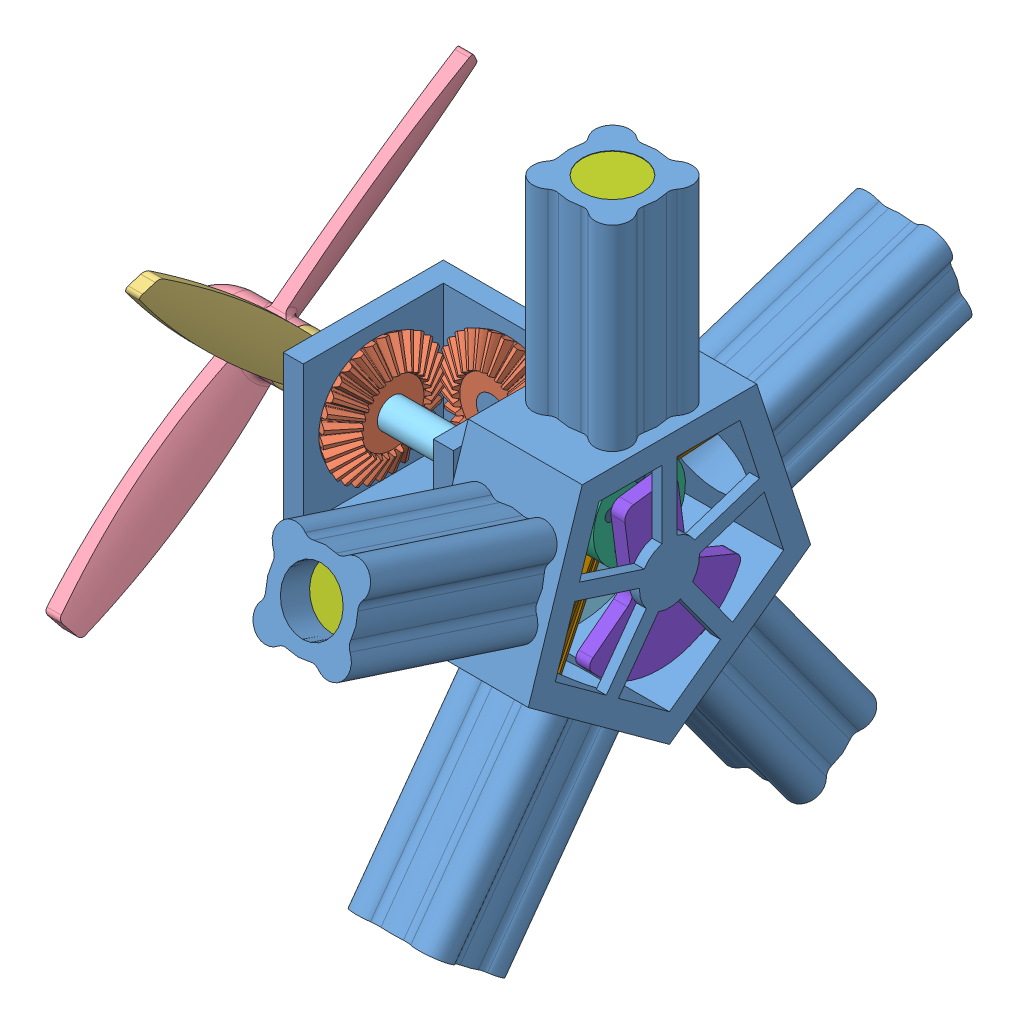
SolidWorks assembly Assembly, configuration Default. Lengths in mm.
Overall size (240.66 300.05 315.49).
28 component instances, 11 part files, 64 mates.
Components (placement in the parent):
- Frame-5: Frame [Default] at (-31.9834 -30.097 217.4511) size (157 300.05 315.49)
- straight bevel gear_am-6: straight bevel gear_am [Bear Propeller Gear] at (10.5166 12.403 147.4521) x (-0.00003 0 1) z (0.262129 0.965033 0.000008) size (11.62 61.25 61.4)
- straight bevel gear_am-7: straight bevel gear_am [Bear Propeller Gear] at (43.0165 12.4031 181.451) x (-1 0 0) z (0 -0.266038 -0.963962) size (11.62 61.25 61.4)
- straight bevel gear_am-8: straight bevel gear_am [Bear Propeller Gear] at (-21.983 12.4031 181.4509) x (1 0 0) z (0 0.96742 -0.253176) size (11.62 61.25 61.4)
- Rear Propeller-1: Rear Propeller [Default] at (-31.9833 12.403 181.4511) x (0 0.679303 0.733858) z (-1 0 0) size (250 25.61 44.95)
- Front Propeller-1: Front Propeller [Default] at (-61.9833 12.403 181.4511) x (0 0.580851 -0.81401) z (-1 0 0) size (250 25.46 57.93)
- Crankshaft Counterweight-1: Crankshaft Counterweight [Default] at (80.0167 45.3295 199.3866) x (0 0.131567 -0.991307) z (-1 0 0) size (75.99 79.21 165)
- Rod Hub-1: Rod Hub [Default] at (80.0167 35.2031 184.4771) x (0 0.608872 0.793269) z (1 0 0) size (97.09 122.53 33)
- Piston-1: Piston [Default] at (96.5166 170.1518 181.4511) x (0 0 1) z (-1 0 0) size (30 35 30)
- Base Counterweight-2: Base Counterweight [Default] at (120.0166 45.3295 199.3866) x (0 0.131567 -0.991307) z (-1 0 0) size (75.99 79.21 47)
- Connecting Rod-2: Connecting Rod [Default] at (96.5167 40.2083 198.6052) x (0 0.100944 0.994892) z (-1 0 0) size (111 13 15)
- Piston-2: Piston [Default] at (96.5166 56.4831 317.1156) x (0 -0.951057 0.309017) z (-1 0 0) size (30 35 30)
- Connecting Rod-3: Connecting Rod [Default] at (96.5167 39.4581 170.1052) x (0 0.089918 -0.995949) z (-1 0 0) size (111 13 15)
- Piston-3: Piston [Default] at (96.5166 54.6302 51.4892) x (0 0.951057 0.309017) z (-1 0 0) size (30 35 30)
- Connecting Rod-4: Connecting Rod [Default] at (96.5167 23.3132 193.6032) x (0 -0.893752 0.448561) z (-1 0 0) size (111 13 15)
- Piston-4: Piston [Default] at (96.5166 -82.2424 250.215) x (0 -0.587785 -0.809017) z (-1 0 0) size (30 35 30)
- Connecting Rod-5: Connecting Rod [Default] at (96.5167 22.8495 175.9892) x (0 -0.866559 -0.499075) z (-1 0 0) size (111 13 15)
- Piston-5: Piston [Default] at (96.5166 -79.9867 114.326) x (0 0.587785 -0.809017) z (-1 0 0) size (30 35 30)
- Hub Pin-1: Hub Pin [Default] at (113.0167 23.3132 193.6032) x (0 0 1) z (-1 0 0) size (6 6 33)
- Hub Pin-2: Hub Pin [Default] at (113.0167 50.1864 184.0827) x (0 0 1) z (-1 0 0) size (6 6 33)
- Hub Pin-3: Hub Pin [Default] at (113.0167 39.4581 170.1052) x (0 0 1) z (-1 0 0) size (6 6 33)
- Hub Pin-4: Hub Pin [Default] at (113.0167 22.8495 175.9892) x (0 0 1) z (-1 0 0) size (6 6 33)
- Hub Pin-5: Hub Pin [Default] at (113.0167 40.2083 198.6052) x (0 0 1) z (-1 0 0) size (6 6 33)
- Piston Pin-1: Piston Pin [Default] at (110.3518 150.1518 181.4511) x (0 0.805023 0.593243) z (-1 0 0) size (10 10 28)
- Piston Pin-2: Piston Pin [Default] at (110.4932 48.4499 70.5103) x (0 0.396271 0.918134) z (-1 0 0) size (10 10 28)
- Piston Pin-3: Piston Pin [Default] at (110.3878 -63.8064 126.0817) x (0 0.161373 0.986894) z (-1 0 0) size (10 10 28)
- Piston Pin-4: Piston Pin [Default] at (110.601 -66.062 238.4593) x (0 0.559209 0.829027) z (-1 0 0) size (10 10 28)
- Piston Pin-5: Piston Pin [Default] at (110.4154 50.3028 298.0944) x (0 0.645386 0.763856) z (-1 0 0) size (10 10 28)
Mates (geometry in assembly coordinates):
- Concentric6: concentric aligned: cylinder of Frame-5 through (10.5164 12.403 155.992) axis (0.00003 0 -1) radius 7.5; cylinder of straight bevel gear_am-6 through (10.516 12.403 166.8) axis (0.00003 0 -1) radius 7.5
- Coincident3: coincident anti-aligned: plane of Frame-5 through (-21.9834 47.403 147.4511) normal (-0.00003 0 1); plane of straight bevel gear_am-6 through (10.5166 12.403 147.452) normal (0.00003 0 -1)
- Concentric7: concentric anti-aligned: cylinder of Frame-5 through (58.0166 12.403 181.4511) axis (-1 0 0) radius 7.5; cylinder of straight bevel gear_am-7 through (23.6687 12.4031 181.451) axis (1 0 0) radius 7.5
- Coincident4: coincident anti-aligned: plane of Frame-5 through (43.0166 47.403 217.4511) normal (-1 0 0); plane of straight bevel gear_am-7 through (43.0166 12.4031 181.451) normal (1 0 0)
- GearMate1: gear = 15 : 15 mm: circle of Bear Propeller Gear-6; cylinder of straight bevel gear_am-7 through (23.6687 12.4031 181.451) axis (1 0 0) radius 7.5
- Concentric8: concentric anti-aligned: cylinder of Frame-5 through (-36.9834 12.403 181.4511) axis (1 0 0) radius 9.5; cylinder of straight bevel gear_am-8 through (-2.6352 12.4031 181.4509) axis (-1 0 0) radius 7.5
- Coincident5: coincident anti-aligned: plane of Frame-5 through (-21.9834 47.403 217.4511) normal (1 0 0); plane of straight bevel gear_am-8 through (-21.9831 12.4031 181.4509) normal (-1 0 0)
- GearMate2: gear = 15 : 15 mm: cylinder of straight bevel gear_am-8 through (-2.6352 12.4031 181.4509) axis (-1 0 0) radius 7.5; cylinder of straight bevel gear_am-6 through (10.516 12.403 166.8) axis (0.00003 0 -1) radius 7.5
- Coincident6: coincident anti-aligned: plane of straight bevel gear_am-8 through (-21.9831 12.4031 181.4509) normal (-1 0 0); plane of Rear Propeller-1 through (-21.9833 12.403 181.4511) normal (1 0 0)
- Concentric9: concentric aligned: cylinder of Frame-5 through (-36.9834 12.403 181.4511) axis (1 0 0) radius 9.5; cylinder of Rear Propeller-1 through (-61.9833 12.403 181.4511) axis (1 0 0) radius 7.5
- Coincident7: coincident anti-aligned: plane of Rear Propeller-1 through (-61.9833 12.403 181.4511) normal (-1 0 0); plane of Front Propeller-1 through (-61.9833 12.403 181.4511) normal (1 0 0)
- Concentric12: concentric anti-aligned: cylinder of Crankshaft Counterweight-1 through (73.0167 35.2031 184.4771) axis (1 0 0) radius 7.5; cylinder of Rod Hub-1 through (113.0167 35.2031 184.4771) axis (-1 0 0) radius 7.5
- Coincident9: coincident anti-aligned: plane of Crankshaft Counterweight-1 through (80.0167 14.143 161.0551) normal (1 0 0); plane of Rod Hub-1 through (80.0167 35.2031 184.4771) normal (-1 0 0)
- Concentric14: concentric aligned: cylinder of Crankshaft Counterweight-1 through (73.0167 35.2031 184.4771) axis (1 0 0) radius 7.5; cylinder of Base Counterweight-2 through (73.0166 35.2031 184.4771) axis (1 0 0) radius 7.5
- Coincident11: coincident aligned: plane of Crankshaft Counterweight-1 through (73.0167 14.143 161.0551) normal (-1 0 0); plane of Base Counterweight-2 through (73.0166 35.2031 184.4771) normal (-1 0 0)
- Concentric20: concentric aligned: cylinder of Frame-5 through (113.0166 12.403 181.4511) axis (1 0 0) radius 7.5; cylinder of Base Counterweight-2 through (113.0166 12.403 181.4511) axis (1 0 0) radius 7.5
- Coincident17: coincident aligned: plane of Frame-5 through (113.0166 12.403 181.4511) normal (-1 0 0); plane of Base Counterweight-2 through (113.0166 14.143 161.0551) normal (-1 0 0)
- Lock10: lock: unknown of straight bevel gear_am-8; unknown of Rear Propeller-1
- Concentric23: concentric anti-aligned: cylinder of Frame-5 through (68.0166 12.403 181.4511) axis (-1 0 0) radius 7.5; cylinder of Crankshaft Counterweight-1 through (-84.9833 12.403 181.4511) axis (1 0 0) radius 7.5
- Lock11: lock: unknown of Front Propeller-1; unknown of Crankshaft Counterweight-1
- Lock12: lock: unknown of straight bevel gear_am-7; unknown of Crankshaft Counterweight-1
- Concentric24: concentric anti-aligned: cylinder of Frame-5 through (96.5166 170.403 181.4511) axis (0 -1 0) radius 15; cylinder of Piston-1 through (96.5166 135.1518 181.4511) axis (0 1 0) radius 15
- Concentric25: concentric anti-aligned: cylinder of Connecting Rod-2 through (89.0167 50.3028 298.0944) axis (1 0 0) radius 5; cylinder of Piston-2 through (111.5166 50.3028 298.0944) axis (-1 0 0) radius 5
- Coincident18: coincident anti-aligned: plane of Connecting Rod-2 through (89.0167 40.2083 198.6052) normal (-1 0 0); plane of Piston-2 through (89.0166 54.1194 288.8065) normal (1 0 0)
- Concentric26: concentric anti-aligned: cylinder of Rod Hub-1 through (113.0167 40.2083 198.6052) axis (-1 0 0) radius 3; cylinder of Connecting Rod-2 through (89.0167 40.2083 198.6052) axis (1 0 0) radius 3
- Coincident19: coincident anti-aligned: plane of Rod Hub-1 through (89.0167 16.9579 198.4812) normal (1 0 0); plane of Connecting Rod-2 through (89.0167 40.2083 198.6052) normal (-1 0 0)
- Concentric27: concentric anti-aligned: cylinder of Frame-5 through (96.5166 61.2277 331.718) axis (0 -0.309017 -0.951057) radius 15; cylinder of Piston-2 through (96.5166 45.6675 283.8286) axis (0 0.309017 0.951057) radius 15
- Concentric28: concentric anti-aligned: cylinder of Connecting Rod-3 through (89.0167 48.4499 70.5103) axis (1 0 0) radius 5; cylinder of Piston-3 through (111.5166 48.4499 70.5103) axis (-1 0 0) radius 5
- Coincident20: coincident anti-aligned: plane of Connecting Rod-3 through (104.0167 39.4581 170.1052) normal (1 0 0); plane of Piston-3 through (104.0166 39.9028 75.781) normal (-1 0 0)
- Concentric29: concentric anti-aligned: cylinder of Rod Hub-1 through (113.0167 39.4581 170.1052) axis (-1 0 0) radius 3; cylinder of Connecting Rod-3 through (89.0167 39.4581 170.1052) axis (1 0 0) radius 3
- Coincident21: coincident anti-aligned: plane of Rod Hub-1 through (89.0167 16.9579 198.4812) normal (1 0 0); plane of Connecting Rod-3 through (89.0167 39.4581 170.1052) normal (-1 0 0)
- Concentric31: concentric anti-aligned: cylinder of Frame-5 through (96.5166 61.2277 31.1841) axis (0 -0.309017 0.951057) radius 15; cylinder of Piston-3 through (96.5166 43.8146 84.7762) axis (0 0.309017 -0.951057) radius 15
- Concentric32: concentric anti-aligned: cylinder of Connecting Rod-4 through (89.0167 -66.062 238.4593) axis (1 0 0) radius 5; cylinder of Piston-4 through (111.5166 -66.062 238.4593) axis (-1 0 0) radius 5
- Coincident22: coincident anti-aligned: plane of Connecting Rod-4 through (104.0167 23.3132 193.6032) normal (1 0 0); plane of Piston-4 through (104.0166 -56.0493 239.2191) normal (-1 0 0)
- Concentric33: concentric anti-aligned: cylinder of Rod Hub-1 through (113.0167 23.3132 193.6032) axis (-1 0 0) radius 3; cylinder of Connecting Rod-4 through (89.0167 23.3132 193.6032) axis (1 0 0) radius 3
- Coincident23: coincident anti-aligned: plane of Rod Hub-1 through (104.0167 16.9579 198.4812) normal (-1 0 0); plane of Connecting Rod-4 through (104.0167 23.3132 193.6032) normal (1 0 0)
- Concentric34: concentric anti-aligned: cylinder of Frame-5 through (96.5166 -115.4216 274.3211) axis (0 0.809017 -0.587785) radius 15; cylinder of Piston-4 through (96.5166 -53.9268 229.6425) axis (0 -0.809017 0.587785) radius 15
- Concentric35: concentric anti-aligned: cylinder of Connecting Rod-5 through (89.0167 -63.8064 126.0817) axis (1 0 0) radius 5; cylinder of Piston-5 through (111.5166 -63.8064 126.0817) axis (-1 0 0) radius 5
- Coincident24: coincident anti-aligned: plane of Connecting Rod-5 through (104.0167 22.8495 175.9892) normal (1 0 0); plane of Piston-5 through (104.0166 -61.4349 135.8391) normal (-1 0 0)
- Concentric36: concentric anti-aligned: cylinder of Rod Hub-1 through (113.0167 22.8495 175.9892) axis (-1 0 0) radius 3; cylinder of Connecting Rod-5 through (89.0167 22.8495 175.9892) axis (1 0 0) radius 3
- Coincident25: coincident anti-aligned: plane of Rod Hub-1 through (89.0167 16.9579 198.4812) normal (1 0 0); plane of Connecting Rod-5 through (89.0167 22.8495 175.9892) normal (-1 0 0)
- Concentric38: concentric anti-aligned: cylinder of Frame-5 through (96.5166 -115.4216 88.581) axis (0 0.809017 0.587785) radius 15; cylinder of Piston-5 through (96.5166 -51.6711 134.8985) axis (0 -0.809017 -0.587785) radius 15
- Parallel4: parallel anti-aligned: plane of Rod Hub-1 through (104.0167 35.2031 184.4771) normal (1 0 0); plane of Piston-1 through (104.0166 142.4979 174.9511) normal (-1 0 0)
- Concentric41: concentric anti-aligned: cylinder of Rod Hub-1 through (89.0167 150.1518 181.4511) axis (1 0 0) radius 5; cylinder of Piston-1 through (111.5166 150.1518 181.4511) axis (-1 0 0) radius 5
- Concentric42: concentric anti-aligned: cylinder of Rod Hub-1 through (113.0167 40.2083 198.6052) axis (-1 0 0) radius 3; cylinder of Hub Pin-5 through (80.0167 40.2083 198.6052) axis (1 0 0) radius 3
- Coincident31: coincident aligned: plane of Rod Hub-1 through (80.0167 35.2031 184.4771) normal (-1 0 0); plane of Hub Pin-5 through (80.0167 40.2083 198.6052) normal (-1 0 0)
- Concentric43: concentric anti-aligned: cylinder of Rod Hub-1 through (113.0167 23.3132 193.6032) axis (-1 0 0) radius 3; cylinder of Hub Pin-1 through (80.0167 23.3132 193.6032) axis (1 0 0) radius 3
- Coincident32: coincident aligned: plane of Rod Hub-1 through (80.0167 35.2031 184.4771) normal (-1 0 0); plane of Hub Pin-1 through (80.0167 23.3132 193.6032) normal (-1 0 0)
- Concentric44: concentric anti-aligned: cylinder of Rod Hub-1 through (113.0167 22.8495 175.9892) axis (-1 0 0) radius 3; cylinder of Hub Pin-4 through (80.0167 22.8495 175.9892) axis (1 0 0) radius 3
- Coincident33: coincident aligned: plane of Rod Hub-1 through (80.0167 35.2031 184.4771) normal (-1 0 0); plane of Hub Pin-4 through (80.0167 22.8495 175.9892) normal (-1 0 0)
- Concentric45: concentric anti-aligned: cylinder of Rod Hub-1 through (113.0167 50.1864 184.0827) axis (-1 0 0) radius 3; cylinder of Hub Pin-2 through (80.0167 50.1864 184.0827) axis (1 0 0) radius 3
- Coincident34: coincident aligned: plane of Rod Hub-1 through (80.0167 35.2031 184.4771) normal (-1 0 0); plane of Hub Pin-2 through (80.0167 50.1864 184.0827) normal (-1 0 0)
- Concentric46: concentric anti-aligned: cylinder of Rod Hub-1 through (113.0167 39.4581 170.1052) axis (-1 0 0) radius 3; cylinder of Hub Pin-3 through (80.0167 39.4581 170.1052) axis (1 0 0) radius 3
- Coincident35: coincident aligned: plane of Rod Hub-1 through (80.0167 35.2031 184.4771) normal (-1 0 0); plane of Hub Pin-3 through (80.0167 39.4581 170.1052) normal (-1 0 0)
- Concentric47: concentric anti-aligned: cylinder of Piston-1 through (111.5166 150.1518 181.4511) axis (-1 0 0) radius 5; cylinder of Piston Pin-1 through (82.3518 150.1518 181.4511) axis (1 0 0) radius 5
- Lock16: lock: unknown of Piston-1; unknown of Piston Pin-1
- Concentric48: concentric anti-aligned: cylinder of Piston-3 through (111.5166 48.4499 70.5103) axis (-1 0 0) radius 5; cylinder of Piston Pin-2 through (82.4932 48.4499 70.5103) axis (1 0 0) radius 5
- Lock17: lock: unknown of Piston-3; unknown of Piston Pin-2
- Concentric49: concentric anti-aligned: cylinder of Piston-5 through (111.5166 -63.8064 126.0817) axis (-1 0 0) radius 5; cylinder of Piston Pin-3 through (82.3878 -63.8064 126.0817) axis (1 0 0) radius 5
- Lock18: lock: unknown of Piston-5; unknown of Piston Pin-3
- Concentric50: concentric anti-aligned: cylinder of Piston-4 through (111.5166 -66.062 238.4593) axis (-1 0 0) radius 5; cylinder of Piston Pin-4 through (82.601 -66.062 238.4593) axis (1 0 0) radius 5
- Lock19: lock: unknown of Piston-4; unknown of Piston Pin-4
- Concentric51: concentric anti-aligned: cylinder of Piston-2 through (111.5166 50.3028 298.0944) axis (-1 0 0) radius 5; cylinder of Piston Pin-5 through (82.4154 50.3028 298.0944) axis (1 0 0) radius 5
- Lock20: lock: unknown of Piston-2; unknown of Piston Pin-5
